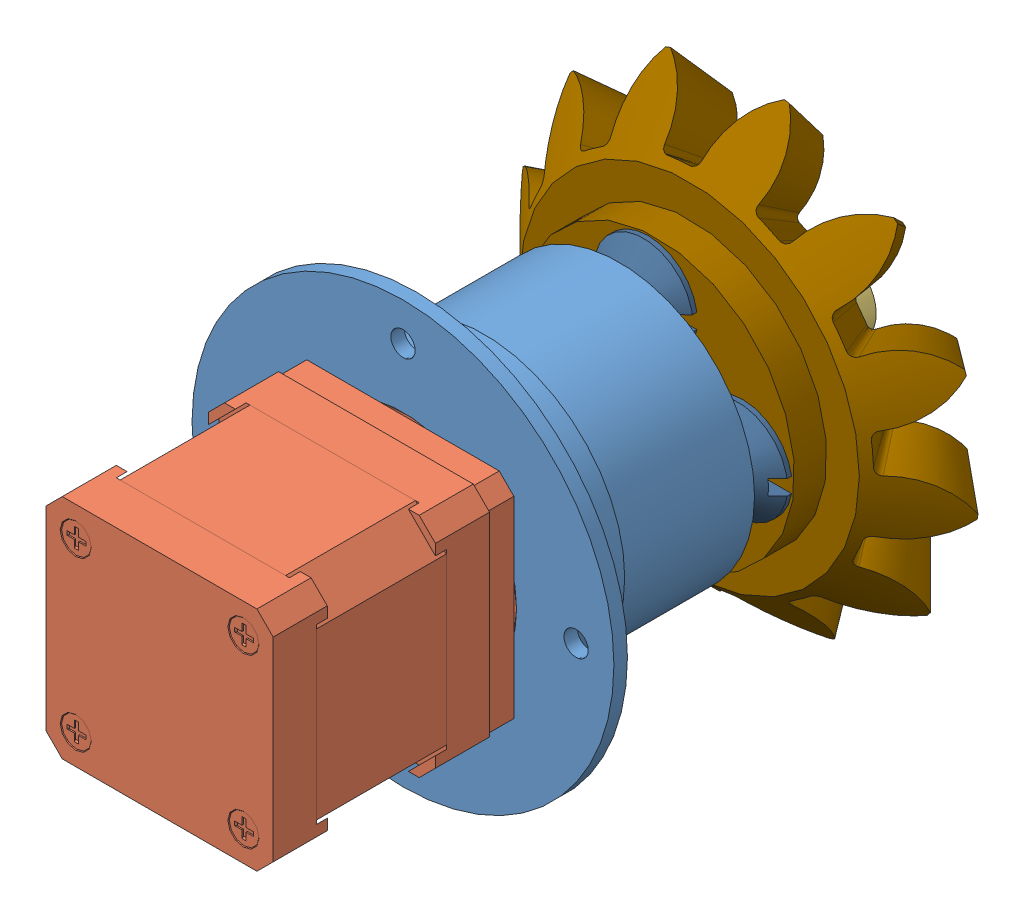
SolidWorks assembly UOM20-4A004-01, configuration Default. Lengths in mm.
Overall size (92.43 92.43 125.5).
33 component instances, 10 part files, 16 mates.
Components (placement in the parent):
- UOM20-4P027-1: UOM20-4P027 [Default] at (41.6885 19.4134 57.3412) x (0 0 -1) z (1 0 0) size (40 78 78)
- 17HS15-1684D-HG10-AR3-1: 17HS15-1684D-HG10-AR3 [Default] at (41.6885 19.4134 62.3412) x (-1 0 0) z (0 0 -1) size (42.88 42 103.5)
- UOM20-4P028-1: UOM20-4P028 [Default] at (41.6885 19.4134 18.8412) x (0 0 -1) z (-0.101971 0.994787 0) size (42 17 17)
- AXK 1528-1: AXK 1528 [Default] at (41.6885 19.4134 15.3412) x (0 0 -1) z (0.812919 0.582377 0) size (4 28 28)
  - AXK_1528___AS_1528___AS_1528_3-1: AXK_1528___AS_1528___AS_1528_3 [Default] x (1 0 0) z (0 -0.309017 0.951057) size (2 5 2)
  - AXK_1528___AS_1528___AS_1528_3-2: AXK_1528___AS_1528___AS_1528_3 [Default] x (1 0 0) z (0 -0.587785 0.809017) size (2 5 2)
  - AXK_1528___AS_1528___AS_1528_3-3: AXK_1528___AS_1528___AS_1528_3 [Default] x (1 0 0) z (0 -0.809017 0.587785) size (2 5 2)
  - AXK_1528___AS_1528___AS_1528_3-4: AXK_1528___AS_1528___AS_1528_3 [Default] x (1 0 0) z (0 -0.951057 0.309017) size (2 5 2)
  - AXK_1528___AS_1528___AS_1528_3-5: AXK_1528___AS_1528___AS_1528_3 [Default] x (1 0 0) z (0 -1 0) size (2 5 2)
  - AXK_1528___AS_1528___AS_1528_3-6: AXK_1528___AS_1528___AS_1528_3 [Default] x (1 0 0) z (0 -0.951057 -0.309017) size (2 5 2)
  - AXK_1528___AS_1528___AS_1528_3-7: AXK_1528___AS_1528___AS_1528_3 [Default] x (1 0 0) z (0 -0.809017 -0.587785) size (2 5 2)
  - AXK_1528___AS_1528___AS_1528_3-8: AXK_1528___AS_1528___AS_1528_3 [Default] x (1 0 0) z (0 -0.587785 -0.809017) size (2 5 2)
  - AXK_1528___AS_1528___AS_1528_3-9: AXK_1528___AS_1528___AS_1528_3 [Default] x (1 0 0) z (0 -0.309017 -0.951057) size (2 5 2)
  - AXK_1528___AS_1528___AS_1528_3-10: AXK_1528___AS_1528___AS_1528_3 [Default] x (1 0 0) z (0 0 -1) size (2 5 2)
  - AXK_1528___AS_1528___AS_1528_3-11: AXK_1528___AS_1528___AS_1528_3 [Default] x (1 0 0) z (0 0.309017 -0.951057) size (2 5 2)
  - AXK_1528___AS_1528___AS_1528_3-12: AXK_1528___AS_1528___AS_1528_3 [Default] x (1 0 0) z (0 0.587785 -0.809017) size (2 5 2)
  - AXK_1528___AS_1528___AS_1528_3-13: AXK_1528___AS_1528___AS_1528_3 [Default] x (1 0 0) z (0 0.809017 -0.587785) size (2 5 2)
  - AXK_1528___AS_1528___AS_1528_3-14: AXK_1528___AS_1528___AS_1528_3 [Default] x (1 0 0) z (0 0.951057 -0.309017) size (2 5 2)
  - AXK_1528___AS_1528___AS_1528_3-15: AXK_1528___AS_1528___AS_1528_3 [Default] x (1 0 0) z (0 1 0) size (2 5 2)
  - AXK_1528___AS_1528___AS_1528_3-16: AXK_1528___AS_1528___AS_1528_3 [Default] x (1 0 0) z (0 0.951057 0.309017) size (2 5 2)
  - AXK_1528___AS_1528___AS_1528_3-17: AXK_1528___AS_1528___AS_1528_3 [Default] x (1 0 0) z (0 0.809017 0.587785) size (2 5 2)
  - AXK_1528___AS_1528___AS_1528_3-18: AXK_1528___AS_1528___AS_1528_3 [Default] x (1 0 0) z (0 0.587785 0.809017) size (2 5 2)
  - AXK_1528___AS_1528___AS_1528_3-19: AXK_1528___AS_1528___AS_1528_3 [Default] x (1 0 0) z (0 0.309017 0.951057) size (2 5 2)
  - AXK_1528___AS_1528___AS_1528_3-20: AXK_1528___AS_1528___AS_1528_3 [Default] at origin size (2 5 2)
  - AXK_1528___AS_1528___AS_1528_24-1: AXK_1528___AS_1528___AS_1528_24 [Default] at origin size (1 28 28)
  - AXK_1528___AS_1528___AS_1528_26-1: AXK_1528___AS_1528___AS_1528_26 [Default] at origin size (1 28 28)
  - AXK_1528___AS_1528___AS_1528_28-1: AXK_1528___AS_1528___AS_1528_28 [Default] at origin size (1.6 28 28)
- 1.5mm spacer-1: 1.5mm spacer [Default] at (41.6885 19.4134 10.3412) x (0.999741 0.022777 0) z (0 0 1) size (28 28 1.5)
- straight miter gear_am-1: straight miter gear_am [PreviewCfg] at (41.6885 19.4134 4.3538) x (0 0 -1) z (0.101971 -0.994787 0) size (25.36 84.27 84.27)
- flat head screw_am-5: flat head screw_am [PreviewCfg] at (41.6885 36.9134 12.0412) x (0 0 1) z (-1 0 0) size (40 18.3 18.08)
- flat head screw_am-6: flat head screw_am [PreviewCfg] at (24.1885 19.4134 12.0412) x (0 0 1) z (-1 0 0) size (40 18.3 18.08)
- flat head screw_am-7: flat head screw_am [PreviewCfg] at (41.6885 1.9134 12.0412) x (0 0 1) z (-1 0 0) size (40 18.3 18.08)
- flat head screw_am-8: flat head screw_am [PreviewCfg] at (59.1885 19.4134 12.0412) x (0 0 1) z (-1 0 0) size (40 18.3 18.08)
Mates (geometry in assembly coordinates):
- Concentric13: concentric aligned: cylinder of UOM20-4P027-1 through (41.6885 19.4134 121.4445) axis (0 0 1) radius 21; cylinder of 17HS15-1684D-HG10-AR3-1 through (41.6885 19.4134 22.3412) axis (0 0 1) radius 21
- Concentric16: concentric aligned: cylinder of UOM20-4P027-1 through (41.6885 36.9134 17.3412) axis (0 0 -1) radius 2.25; circle of 17HS15-1684D-HG10-AR3-1
- Coincident7: coincident anti-aligned: plane of UOM20-4P027-1 through (41.6885 40.4134 22.3412) normal (0 0 1); plane of 17HS15-1684D-HG10-AR3-1 through (41.6885 19.4134 22.3412) normal (0 0 -1)
- Coincident10: coincident anti-aligned: plane of UOM20-4P027-1 through (41.6885 27.9134 17.3412) normal (0 0 -1); plane of AXK 1528-1/AXK_1528___AS_1528___AS_1528_26-1 through (33.5352 30.7942 17.3412) normal (0 0 1)
- Concentric18: concentric aligned: cylinder of 17HS15-1684D-HG10-AR3-1 through (41.6885 19.4134 15.0412) axis (0 0 1) radius 4; cylinder of UOM20-4P028-1 through (41.6885 19.4134 -23.1588) axis (0 0 1) radius 4
- Distance3: distance = 1.5 mm anti-aligned: plane of 17HS15-1684D-HG10-AR3-1 through (41.6885 19.4134 20.3412) normal (0 0 -1); plane of UOM20-4P028-1 through (41.6885 19.4134 18.8412) normal (0 0 1)
- Concentric20: concentric anti-aligned: cylinder of UOM20-4P028-1 through (41.6885 19.4134 13.8412) axis (0 0 1) radius 7.5; circle of AXK 1528-1/AXK_1528___AS_1528___AS_1528_24-1
- Concentric21: concentric anti-aligned: cylinder of UOM20-4P028-1 through (41.6885 19.4134 -23.1588) axis (0 0 1) radius 7.5; cylinder of 1.5mm spacer-1 through (41.6885 19.4134 11.8412) axis (0 0 -1) radius 7.5
- Coincident11: coincident anti-aligned: plane of UOM20-4P028-1 through (41.6885 19.4134 11.8412) normal (0 0 -1); plane of 1.5mm spacer-1 through (41.6885 19.4134 11.8412) normal (0 0 1)
- Parallel9: parallel aligned: plane of UOM20-4P028-1 through (80.6907 29.1714 14.3839) normal (0.101971 -0.994787 0); plane of straight miter gear_am-1 through (79.9944 29.1001 -36.5613) normal (0.101971 -0.994787 0)
- Concentric2592: concentric anti-aligned: cylinder of UOM20-4P028-1 through (41.6885 19.4134 -23.1588) axis (0 0 1) radius 7.5; cylinder of straight miter gear_am-1 through (41.6885 19.4134 10.3412) axis (0 0 -1) radius 25.4
- Coincident29: coincident anti-aligned: plane of 1.5mm spacer-1 through (41.6885 19.4134 10.3412) normal (0 0 -1); plane of straight miter gear_am-1 through (41.6885 19.4134 10.3412) normal (0 0 1)
- Coincident46: coincident aligned: cone of UOM20-4P027-1 through (41.6885 36.9134 17.3412) axis (0 0 1); cone of flat head screw_am-5 through (41.6885 36.9134 12.8912) axis (0 0 1)
- Coincident47: coincident aligned: cone of UOM20-4P027-1 through (24.1885 19.4134 17.3412) axis (0 0 1); cone of flat head screw_am-6 through (24.1885 19.4134 12.8912) axis (0 0 1)
- Coincident48: coincident aligned: cone of UOM20-4P027-1 through (41.6885 1.9134 17.3412) axis (0 0 1); cone of flat head screw_am-7 through (41.6885 1.9134 12.8912) axis (0 0 1)
- Coincident49: coincident aligned: cone of UOM20-4P027-1 through (59.1885 19.4134 17.3412) axis (0 0 1); cone of flat head screw_am-8 through (59.1885 19.4134 12.8912) axis (0 0 1)
